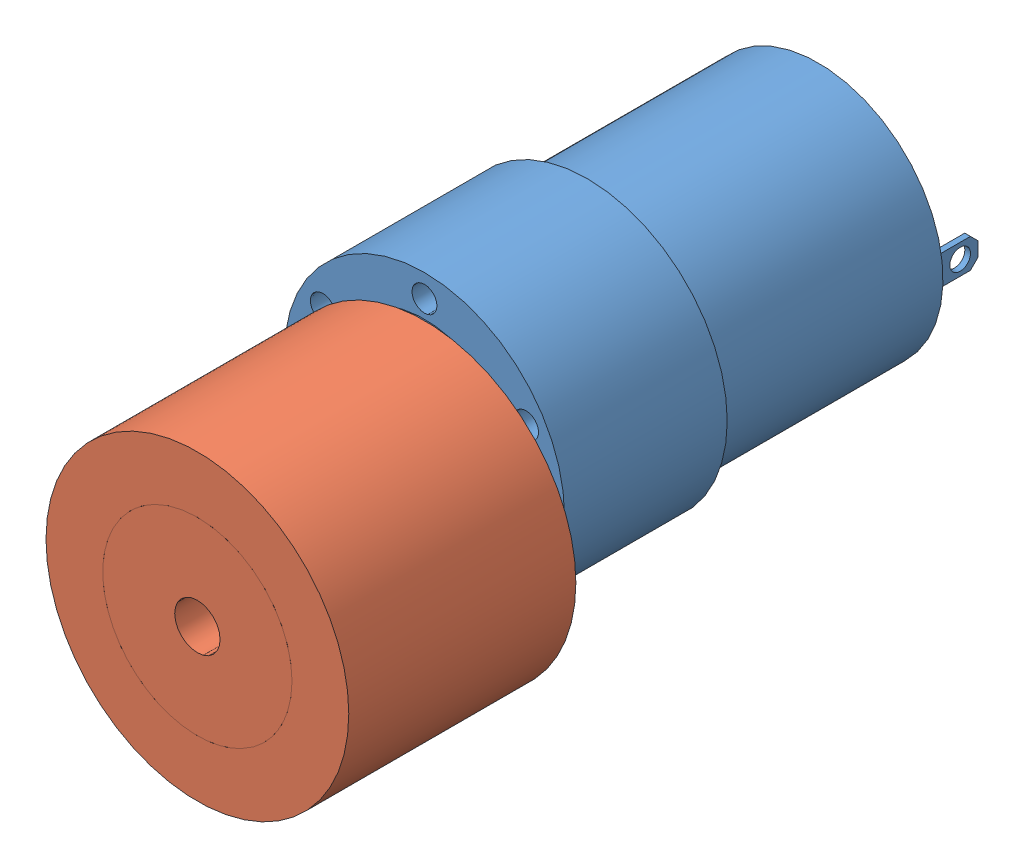
SolidWorks assembly Motor+Rueda, configuration Predeterminado. Lengths in mm.
Overall size (45.5 40 94.75).
2 component instances, 2 part files, 0 mates.
Components (placement in the parent):
- Titan-37mm-500rpm-2: Titan-37mm-500rpm [Predeterminado] at (-8.182 1.2078 75.625) x (0 1 0) z (0 0 1) size (37 37 78.75)
- js4030-wheel-cad-1: js4030-wheel-cad [Predeterminado] at (-21.4262 1.7536 159.125) x (-1 0 0) z (0 0 -1) size (40 40 30)
